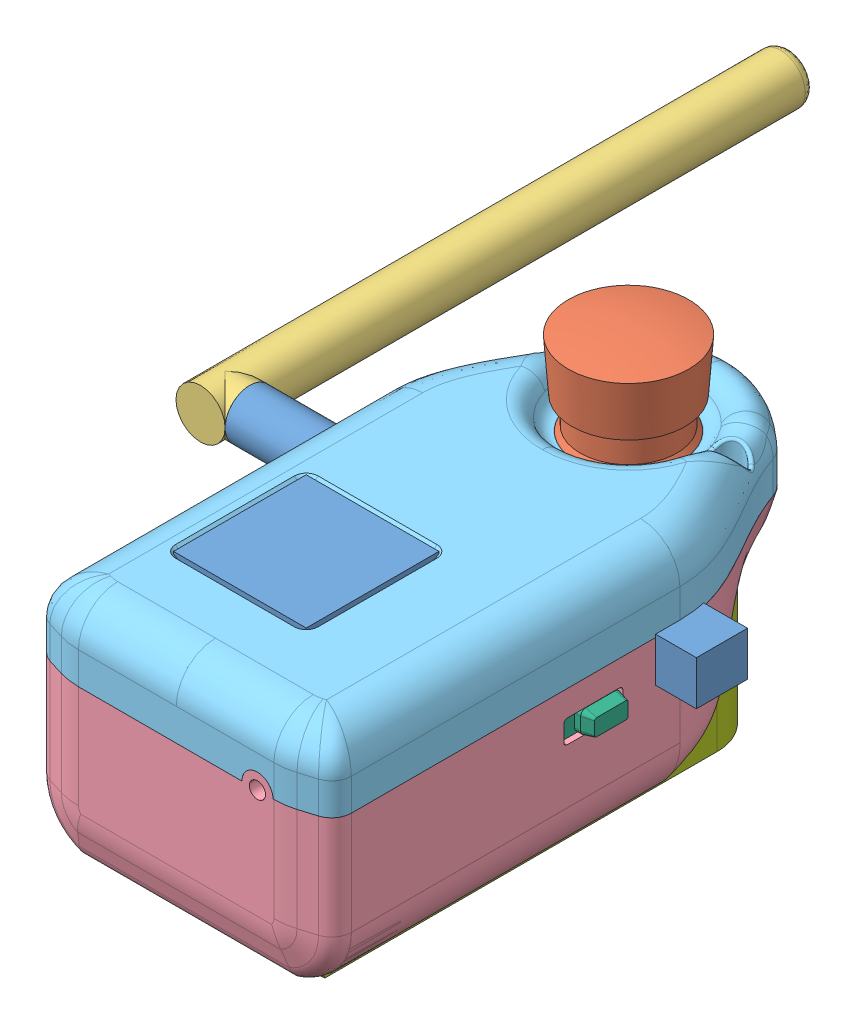
SolidWorks assembly MASTER_doomsday_v1, configuration Default. Lengths in mm.
Overall size (109.7 79.73 194.86).
7 component instances, 7 part files, 5 mates.
Components (placement in the parent):
- DOOM_ELT_dummy^MASTER_doomsday_v1-1: DOOM_ELT_dummy^MASTER_doomsday_v1 [Default] at origin size (109.7 67.73 93.36) (virtual)
- button-1: button [Default] at (0 48.5 -87) x (0 -1 0) z (0 0 1) size (47.5 24.5 24.5)
- antenna-1: antenna [Default] at (-50.55 21 -60.5) x (0 0 -1) z (1 0 0) size (120 10 10)
- bottom^MASTER_doomsday_v1-1: bottom^MASTER_doomsday_v1 [Default] at origin size (62.84 40.43 113.83)
- cover^MASTER_doomsday_v1-1: cover^MASTER_doomsday_v1 [Default] at origin size (64.87 18.5 114.75)
- slider^MASTER_doomsday_v1-1: slider^MASTER_doomsday_v1 [Default] at origin size (9 7.4 16)
- clip^MASTER_doomsday_v1-1: clip^MASTER_doomsday_v1 [Default] at origin size (30 30.59 90)
Mates (geometry in assembly coordinates):
- Distance1: distance = 30 mm anti-aligned: plane of button-1 through (10.68 30 -87) normal (0 -1 0); plane of assembly through (0 0 0) normal (0 1 0)
- Distance2: distance = 0 mm aligned: plane of button-1; plane of assembly through (0 0 0) normal (1 0 0)
- Distance3: distance = 87 mm aligned: plane of button-1 through (0 48.5 -87) normal (0 0 1); plane of assembly through (0 0 0) normal (0 0 1)
- Coincident4: coincident anti-aligned: plane of DOOM_ELT_dummy^MASTER_doomsday_v1-1 through (-50.55 21 -60.5) normal (-1 0 0); plane of antenna-1 through (-50.55 21 -60.5) normal (1 0 0)
- Concentric1: concentric anti-aligned: circle of DOOM_ELT_dummy^MASTER_doomsday_v1-1; circle of antenna-1
